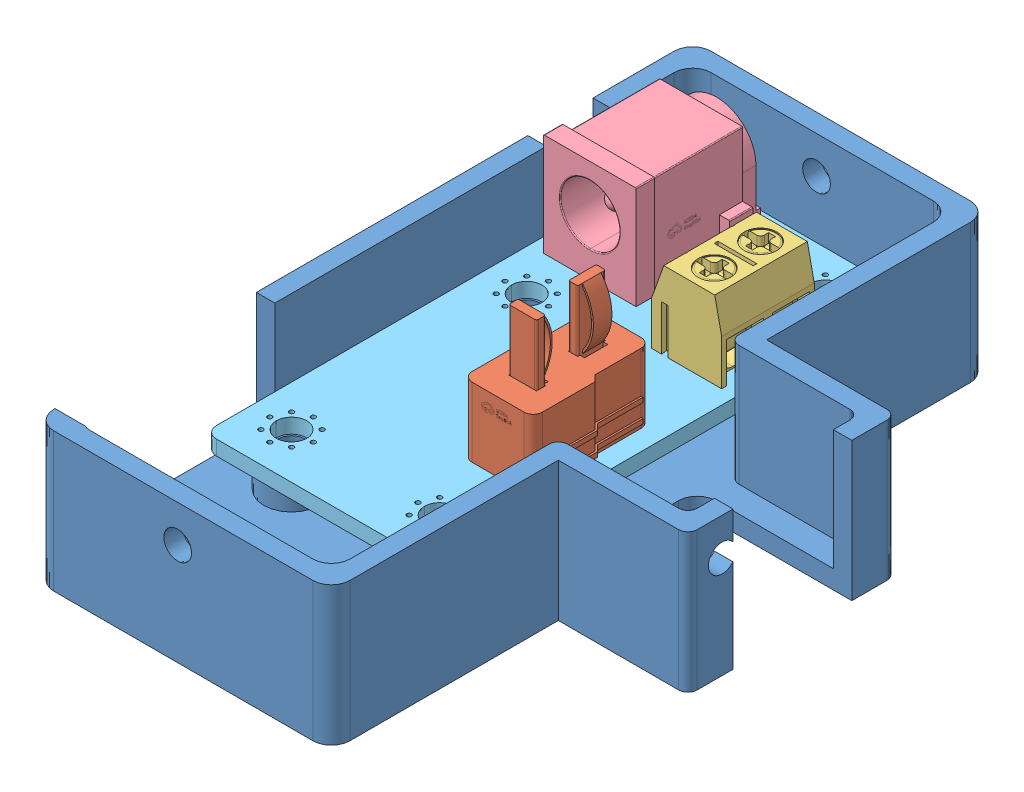
SolidWorks assembly 电池集线器装配, configuration 默认. Lengths in mm.
Overall size (46 21.7 71).
9 component instances, 5 part files, 3 mates.
Components (placement in the parent):
- 电池供电槽-1: 电池供电槽 [默认] at (4.6144 -0.7391 74.5) size (46 15 71)
- UPbotBatteryHub.step-1: UPbotBatteryHub.step [默认] at (-22.6527 5.2609 41.4153) x (1 0 0) z (0 1 0) size (25.37 50.77 19.1)
  - CN2~CONN-TH_AM-1015B-M~CONN-TH_AM-1015B-M~y3ml.step-1: CN2~CONN-TH_AM-1015B-M~CONN-TH_AM-1015B-M~y3ml.step [默认] at (19.939 -32.8931 1.6) x (0 1 0) z (0 0 1) size (13.3 8 19.1)
    - CONN-TH_AM-1015B-M~CONN-TH_AM-1015B-M~y3ml.step-1: CONN-TH_AM-1015B-M~CONN-TH_AM-1015B-M~y3ml.step [默认] at origin size (13.3 8 19.1)
  - U3~CONN-TH_P5.00_KF301-5.0-2P~CONN-TH_P5.00_KF301-5.0-2P~y3ml.step-1: U3~CONN-TH_P5.00_KF301-5.0-2P~CONN-TH_P5.00_KF301-5.0-2P~y3ml.step [默认] at (20.066 -14.224 1.6) x (0 1 0) z (0 0 1) size (10.61 7.61 13.41)
    - CONN-TH_P5.00_KF301-5.0-2P~CONN-TH_P5.00_KF301-5.0-2P~y3ml.step-1: CONN-TH_P5.00_KF301-5.0-2P~CONN-TH_P5.00_KF301-5.0-2P~y3ml.step [默认] at origin size (10.61 7.61 13.41)
  - DC1~DC-IN-TH_DC550200-1095-2H~DC-IN-TH_DC550200-1095-2H~y3ml.step-1: DC1~DC-IN-TH_DC550200-1095-2H~DC-IN-TH_DC550200-1095-2H~y3ml.step [默认] at (8.89 -5.334 1.6) size (10.6 14.2 14.1)
    - DC-IN-TH_DC550200-1095-2H~DC-IN-TH_DC550200-1095-2H~y3ml.step-1: DC-IN-TH_DC550200-1095-2H~DC-IN-TH_DC550200-1095-2H~y3ml.step [默认] at origin size (10.6 14.2 14.1)
  - Board~y3ml.step-1: Board~y3ml.step [默认] at origin size (25.37 50.77 1.6)
Mates (geometry in assembly coordinates):
- 平行1: parallel anti-aligned: plane of 电池供电槽-1 through (4.6144 1.2609 74.5) normal (0 1 0); plane of UPbotBatteryHub.step-1/Board~y3ml.step-1 through (-10.0796 5.2609 67.1964) normal (0 -1 0)
- 平行2: parallel aligned: plane of 电池供电槽-1 through (-25.666 14.2609 108) normal (-1 0 0); plane of UPbotBatteryHub.step-1/Board~y3ml.step-1 through (-22.767 5.2609 91.3264) normal (-1 0 0)
- 重合3: coincident anti-aligned: plane of 电池供电槽-1 through (-18.3347 5.2609 87.6434) normal (0 1 0); plane of UPbotBatteryHub.step-1/Board~y3ml.step-1 through (-10.0796 5.2609 67.1964) normal (0 -1 0)
